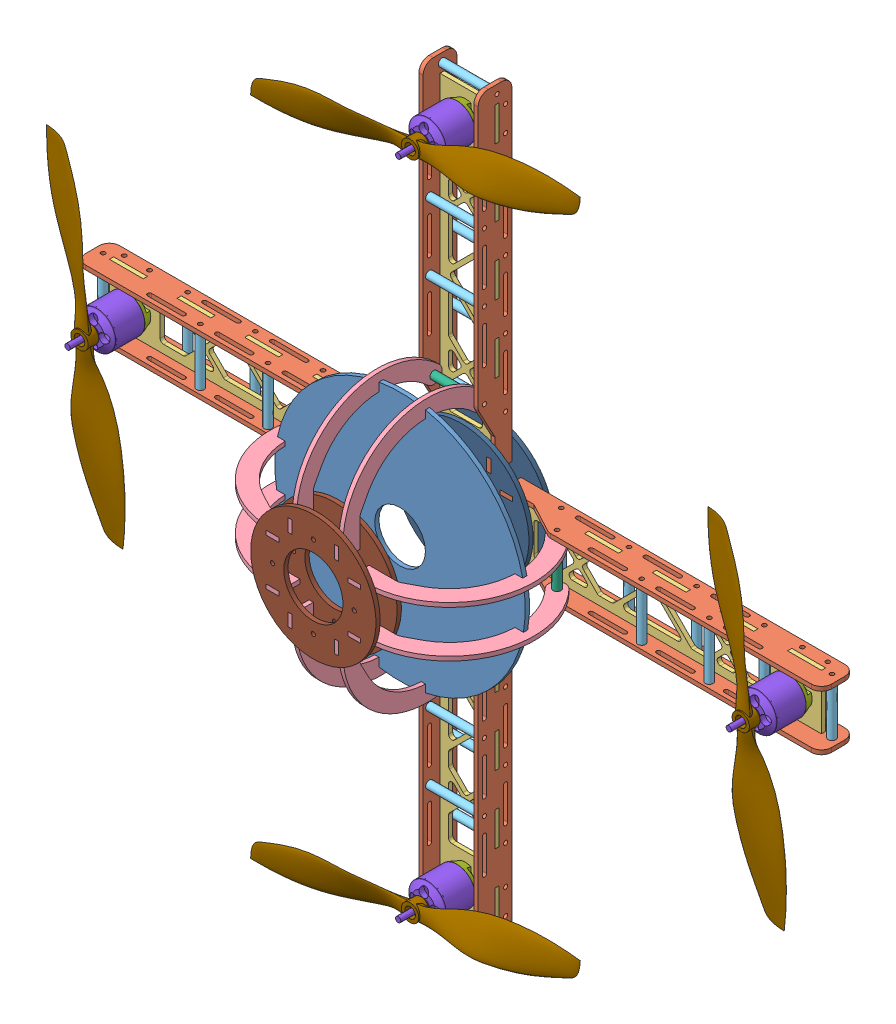
SolidWorks assembly Final Assy, configuration Default. Lengths in mm.
Overall size (588.25 588.25 130.02).
77 component instances, 11 part files, 24 mates.
Components (placement in the parent):
- center - F-1: center - F [Default] at (-38.5834 7.7412 15.1007) size (187.96 187.96 3.17)
- arm - assy - F-1: arm - assy - F [Default] at (-153.8575 14.0052 -35.4357) x (1 0 0) z (0 1 0) size (268.19 130.02 255.49)
  - arm - F-1: arm - F [Default] at (7.8754 -24.9369 12.786) size (250.83 28.57 3.17)
  - arm-center - F-1: arm-center - F [Default] at (-76.2706 -4.6579 -11.069) x (1 0 0) z (0 1 0) size (238.12 44.45 3.17)
  - arm - F-2: arm - F [Default] at (7.8754 -24.9369 -28.489) size (250.83 28.57 3.17)
  - arm-piece - F-1: arm-piece - F [Default] at (-66.1286 -74.8964 9.611) size (73.03 112.55 3.17)
  - arm-piece - F-2: arm-piece - F [Default] at (-66.1286 -74.8964 -25.314) size (73.03 112.55 3.17)
  - spacer - F-1: spacer - F [Default] at (-75.7599 -12.5954 -25.314) size (5.71 5.71 38.1)
  - spacer - F-2: spacer - F [Default] at (51.2401 3.2796 -25.314) size (5.71 5.71 38.1)
  - spacer - F-3: spacer - F [Default] at (-101.1599 3.2796 -25.314) size (5.71 5.71 38.1)
  - spacer - F-4: spacer - F [Default] at (-24.9599 -12.5954 -25.314) size (5.71 5.71 38.1)
  - spacer - F-5: spacer - F [Default] at (-50.3599 3.2796 -25.314) size (5.71 5.71 38.1)
  - spacer - F-6: spacer - F [Default] at (0.4401 3.2796 -25.314) size (5.71 5.71 38.1)
  - spacer - F-7: spacer - F [Default] at (-158.3099 -3.0704 -25.314) size (5.71 5.71 38.1)
  - spacer - Short - F-1: spacer - Short - F [Default] at (38.5401 -12.5954 -22.139) size (5.71 5.71 31.75)
  - motor-assy-1: motor-assy [Default] at (-134.2321 -7.4751 -6.6678) x (-1 0 0) z (0 0 1) size (91.88 50.5 255.49)
    - motor-bot2-1: motor-bot2 [Default] at (-1.3226 -2.8172 0.4038) size (27.94 6.5 27.94)
    - motor2-1: motor2 [Default] at (-1.3226 3.6828 0.4038) size (28 44 28)
    - prop-1: prop [Default] at (-1.3226 34.6828 0.4038) x (0.974272 0 -0.225375) z (0.225375 0 0.974272) size (35.55 10.91 254.01)
- arm - assy - F-4: arm - assy - F [Default] at (76.6907 1.4772 -35.4357) x (-1 0 0) z (0 -1 0) size (268.19 130.02 255.49)
  - arm - F-1: arm - F [Default] at (7.8754 -24.9369 12.786) size (250.83 28.57 3.17)
  - arm-center - F-1: arm-center - F [Default] at (-76.2706 -4.6579 -11.069) x (1 0 0) z (0 1 0) size (238.12 44.45 3.17)
  - arm - F-2: arm - F [Default] at (7.8754 -24.9369 -28.489) size (250.83 28.57 3.17)
  - arm-piece - F-1: arm-piece - F [Default] at (-66.1286 -74.8964 9.611) size (73.03 112.55 3.17)
  - arm-piece - F-2: arm-piece - F [Default] at (-66.1286 -74.8964 -25.314) size (73.03 112.55 3.17)
  - spacer - F-1: spacer - F [Default] at (-75.7599 -12.5954 -25.314) size (5.71 5.71 38.1)
  - spacer - F-2: spacer - F [Default] at (51.2401 3.2796 -25.314) size (5.71 5.71 38.1)
  - spacer - F-3: spacer - F [Default] at (-101.1599 3.2796 -25.314) size (5.71 5.71 38.1)
  - spacer - F-4: spacer - F [Default] at (-24.9599 -12.5954 -25.314) size (5.71 5.71 38.1)
  - spacer - F-5: spacer - F [Default] at (-50.3599 3.2796 -25.314) size (5.71 5.71 38.1)
  - spacer - F-6: spacer - F [Default] at (0.4401 3.2796 -25.314) size (5.71 5.71 38.1)
  - spacer - F-7: spacer - F [Default] at (-158.3099 -3.0704 -25.314) size (5.71 5.71 38.1)
  - spacer - Short - F-1: spacer - Short - F [Default] at (38.5401 -12.5954 -22.139) size (5.71 5.71 31.75)
  - motor-assy-1: motor-assy [Default] at (-134.2321 -7.4751 -6.6678) x (-1 0 0) z (0 0 1) size (91.88 50.5 255.49)
    - motor-bot2-1: motor-bot2 [Default] at (-1.3226 -2.8172 0.4038) size (27.94 6.5 27.94)
    - motor2-1: motor2 [Default] at (-1.3226 3.6828 0.4038) size (28 44 28)
    - prop-1: prop [Default] at (-1.3226 34.6828 0.4038) x (0.974272 0 -0.225375) z (0.225375 0 0.974272) size (35.55 10.91 254.01)
- bot-circ - F-1: bot-circ - F [Default] at (-35.3836 7.7412 -30.7778) size (101.6 101.6 3.17)
- arm - assy - F-5: arm - assy - F [Default] at (-44.8474 -107.5329 -35.4357) x (0 1 0) z (-1 0 0) size (268.19 130.02 255.49)
  - arm - F-1: arm - F [Default] at (7.8754 -24.9369 12.786) size (250.83 28.57 3.17)
  - arm-center - F-1: arm-center - F [Default] at (-76.2706 -4.6579 -11.069) x (1 0 0) z (0 1 0) size (238.12 44.45 3.17)
  - arm - F-2: arm - F [Default] at (7.8754 -24.9369 -28.489) size (250.83 28.57 3.17)
  - arm-piece - F-1: arm-piece - F [Default] at (-66.1286 -74.8964 9.611) size (73.03 112.55 3.17)
  - arm-piece - F-2: arm-piece - F [Default] at (-66.1286 -74.8964 -25.314) size (73.03 112.55 3.17)
  - spacer - F-1: spacer - F [Default] at (-75.7599 -12.5954 -25.314) size (5.71 5.71 38.1)
  - spacer - F-2: spacer - F [Default] at (51.2401 3.2796 -25.314) size (5.71 5.71 38.1)
  - spacer - F-3: spacer - F [Default] at (-101.1599 3.2796 -25.314) size (5.71 5.71 38.1)
  - spacer - F-4: spacer - F [Default] at (-24.9599 -12.5954 -25.314) size (5.71 5.71 38.1)
  - spacer - F-5: spacer - F [Default] at (-50.3599 3.2796 -25.314) size (5.71 5.71 38.1)
  - spacer - F-6: spacer - F [Default] at (0.4401 3.2796 -25.314) size (5.71 5.71 38.1)
  - spacer - F-7: spacer - F [Default] at (-158.3099 -3.0704 -25.314) size (5.71 5.71 38.1)
  - spacer - Short - F-1: spacer - Short - F [Default] at (38.5401 -12.5954 -22.139) size (5.71 5.71 31.75)
  - motor-assy-1: motor-assy [Default] at (-134.2321 -7.4751 -6.6678) x (-1 0 0) z (0 0 1) size (91.88 50.5 255.49)
    - motor-bot2-1: motor-bot2 [Default] at (-1.3226 -2.8172 0.4038) size (27.94 6.5 27.94)
    - motor2-1: motor2 [Default] at (-1.3226 3.6828 0.4038) size (28 44 28)
    - prop-1: prop [Default] at (-1.3226 34.6828 0.4038) x (0.974272 0 -0.225375) z (0.225375 0 0.974272) size (35.55 10.91 254.01)
- arm - assy - F-6: arm - assy - F [Default] at (-32.3194 123.0153 -35.4357) x (0 -1 0) z (1 0 0) size (268.19 130.02 255.49)
  - arm - F-1: arm - F [Default] at (7.8754 -24.9369 12.786) size (250.83 28.57 3.17)
  - arm-center - F-1: arm-center - F [Default] at (-76.2706 -4.6579 -11.069) x (1 0 0) z (0 1 0) size (238.12 44.45 3.17)
  - arm - F-2: arm - F [Default] at (7.8754 -24.9369 -28.489) size (250.83 28.57 3.17)
  - arm-piece - F-1: arm-piece - F [Default] at (-66.1286 -74.8964 9.611) size (73.03 112.55 3.17)
  - arm-piece - F-2: arm-piece - F [Default] at (-66.1286 -74.8964 -25.314) size (73.03 112.55 3.17)
  - spacer - F-1: spacer - F [Default] at (-75.7599 -12.5954 -25.314) size (5.71 5.71 38.1)
  - spacer - F-2: spacer - F [Default] at (51.2401 3.2796 -25.314) size (5.71 5.71 38.1)
  - spacer - F-3: spacer - F [Default] at (-101.1599 3.2796 -25.314) size (5.71 5.71 38.1)
  - spacer - F-4: spacer - F [Default] at (-24.9599 -12.5954 -25.314) size (5.71 5.71 38.1)
  - spacer - F-5: spacer - F [Default] at (-50.3599 3.2796 -25.314) size (5.71 5.71 38.1)
  - spacer - F-6: spacer - F [Default] at (0.4401 3.2796 -25.314) size (5.71 5.71 38.1)
  - spacer - F-7: spacer - F [Default] at (-158.3099 -3.0704 -25.314) size (5.71 5.71 38.1)
  - spacer - Short - F-1: spacer - Short - F [Default] at (38.5401 -12.5954 -22.139) size (5.71 5.71 31.75)
  - motor-assy-1: motor-assy [Default] at (-134.2321 -7.4751 -6.6678) x (-1 0 0) z (0 0 1) size (91.88 50.5 255.49)
    - motor-bot2-1: motor-bot2 [Default] at (-1.3226 -2.8172 0.4038) size (27.94 6.5 27.94)
    - motor2-1: motor2 [Default] at (-1.3226 3.6828 0.4038) size (28 44 28)
    - prop-1: prop [Default] at (-1.3226 34.6828 0.4038) x (0.974272 0 -0.225375) z (0.225375 0 0.974272) size (35.55 10.91 254.01)
- bot-circ - F-2: bot-circ - F [Default] at (-35.3836 7.7412 -46.6528) size (101.6 101.6 3.17)
- top-circ - F-1: top-circ - F [Default] at (-38.5828 7.7412 80.1882) size (93.98 93.98 3.17)
- top-circ - F-2: top-circ - F [Default] at (-38.5828 7.7406 64.3132) size (93.98 93.98 3.17)
Mates (geometry in assembly coordinates):
- Coincident1: coincident anti-aligned: plane of center - F-1 through (-127.3576 7.7412 18.2757) normal (-1 0 0); plane of arm - assy - F-1/arm-piece - F-1 through (-127.3576 26.7912 15.1007) normal (1 0 0)
- Coincident2: coincident anti-aligned: plane of center - F-1 through (-38.5834 7.7412 18.2757) normal (0 0 1); plane of arm - assy - F-1/arm-piece - F-1 through (-127.3576 26.7912 18.2757) normal (0 0 -1)
- Coincident3: coincident anti-aligned: plane of center - F-1 through (-38.5834 -11.3088 18.2757) normal (0 1 0); plane of arm - assy - F-1/arm-piece - F-2 through (-74.0424 -11.3088 16.6882) normal (0 -1 0)
- Coincident4: coincident anti-aligned: plane of center - F-1 through (50.1908 7.7412 18.2757) normal (1 0 0); plane of arm - assy - F-4/arm-piece - F-1 through (50.1908 -11.3088 15.1007) normal (-1 0 0)
- Coincident5: coincident anti-aligned: plane of center - F-1 through (-38.5834 7.7412 18.2757) normal (0 0 1); plane of arm - assy - F-4/arm-piece - F-1 through (50.1908 -11.3088 18.2757) normal (0 0 -1)
- Coincident6: coincident anti-aligned: plane of center - F-1 through (-38.5834 26.7912 18.2757) normal (0 -1 0); plane of arm - assy - F-4/arm-piece - F-2 through (-3.1244 26.7912 16.6882) normal (0 1 0)
- Coincident7: coincident anti-aligned: plane of arm - assy - F-4/arm - F-1 through (-9.4744 -14.4838 -46.6528) normal (-1 0 0); plane of bot-circ - F-1 through (-9.4744 -11.3088 -27.6028) normal (1 0 0)
- Coincident9: coincident anti-aligned: plane of arm - assy - F-4/arm - F-1 through (37.8331 -11.3088 -23.1578) normal (0 1 0); plane of bot-circ - F-1 through (0.0506 -11.3088 -27.6028) normal (0 -1 0)
- Coincident10: coincident aligned: plane of arm - assy - F-4/arm - F-1 through (-9.4744 -14.4838 -27.6028) normal (0 0 1); plane of bot-circ - F-1 through (-38.5574 7.7412 -27.6028) normal (0 0 1)
- Coincident11: coincident aligned: line of center - F-1 through (-19.5334 -81.033 18.2757) axis (0 0 -1); line of arm - assy - F-5/arm-piece - F-2 through (-19.5334 -81.033 18.2757) axis (0 0 -1)
- Coincident12: coincident anti-aligned: plane of center - F-1 through (-38.5834 -81.033 18.2757) normal (0 -1 0); plane of arm - assy - F-5/arm-piece - F-1 through (-57.6334 -81.033 15.1007) normal (0 1 0)
- Coincident13: coincident anti-aligned: plane of center - F-1 through (-38.5834 7.7412 18.2757) normal (0 0 1); plane of arm - assy - F-5/arm-piece - F-2 through (-22.7084 -81.033 18.2757) normal (0 0 -1)
- Coincident14: coincident anti-aligned: plane of center - F-1 through (-38.5834 96.5154 18.2757) normal (0 1 0); plane of arm - assy - F-6/arm-piece - F-1 through (-19.5334 96.5154 15.1007) normal (0 -1 0)
- Coincident15: coincident anti-aligned: plane of center - F-1 through (-38.5834 7.7412 18.2757) normal (0 0 1); plane of arm - assy - F-6/arm-piece - F-1 through (-19.5334 96.5154 18.2757) normal (0 0 -1)
- Coincident16: coincident anti-aligned: plane of center - F-1 through (-19.5334 7.7412 18.2757) normal (-1 0 0); plane of arm - assy - F-6/arm-piece - F-1 through (-19.5334 43.2003 16.6882) normal (1 0 0)
- Coincident23: coincident anti-aligned: plane of arm - assy - F-1/arm-piece - F-1 through (-74.0424 26.7912 80.1882) normal (-1 0 0); plane of top-circ - F-1 through (-74.0424 26.7912 83.3632) normal (1 0 0)
- Coincident24: coincident anti-aligned: plane of arm - assy - F-1/arm-piece - F-1 through (-74.0424 26.7912 16.6882) normal (0 1 0); plane of top-circ - F-1 through (-70.8674 26.7912 83.3632) normal (0 -1 0)
- Coincident25: coincident aligned: plane of arm - assy - F-1/arm-piece - F-1 through (-74.0424 26.7912 83.3632) normal (0 0 1); plane of top-circ - F-1 through (-38.5828 7.7412 83.3632) normal (0 0 1)
- Coincident26: coincident anti-aligned: plane of arm - assy - F-4/arm-piece - F-2 through (-3.1244 23.6162 67.4882) normal (0 0 -1); plane of top-circ - F-2 through (-38.5828 7.7406 67.4882) normal (0 0 1)
- Coincident27: coincident anti-aligned: plane of arm - assy - F-6/arm-piece - F-1 through (-19.5334 33.6753 64.3132) normal (0 -1 0); plane of top-circ - F-2 through (-22.7078 33.6753 67.4882) normal (0 1 0)
- Coincident28: coincident anti-aligned: plane of arm - assy - F-1/arm-piece - F-1 through (-64.5174 26.7912 64.3132) normal (1 0 0); plane of top-circ - F-2 through (-64.5174 23.6156 67.4882) normal (-1 0 0)
- Coincident31: coincident anti-aligned: plane of arm - assy - F-1/arm - F-2 through (-298.1974 -11.3088 -43.4778) normal (0 0 -1); plane of bot-circ - F-2 through (-38.5574 7.7412 -43.4778) normal (0 0 1)
- Concentric9: concentric aligned: circle of bot-circ - F-1; circle of bot-circ - F-2
- Concentric10: concentric aligned: circle of bot-circ - F-1; circle of bot-circ - F-2
